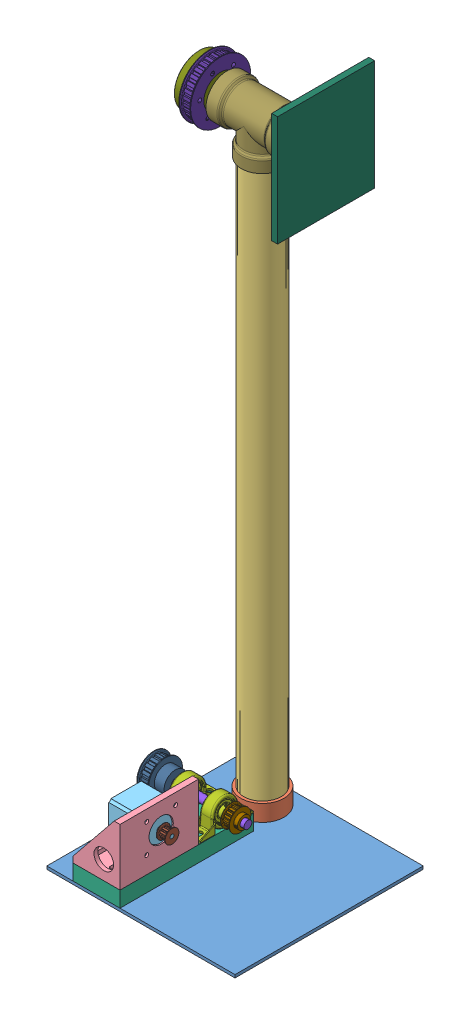
SolidWorks assembly Assem2, configuration Default. Lengths in mm.
Overall size (318.47 1076.8 338.99).
24 component instances, 19 part files, 3 mates.
Components (placement in the parent):
- Base Plate-1: Base Plate [Default] at (167.7214 104.1568 1085.8312) size (304.8 943.9 304.8)
  - Base Plate-1: Base Plate [Default] at origin size (304.8 4.76 304.8)
  - 1608T194_STANDARD-WALL BLACK ABS PIPE   PIPE FITTING-1: 1608T194_STANDARD-WALL BLACK ABS PIPE   PIPE FITTING [1608T194] at (88.9 4.7625 -260.35) x (0 -1 0) z (0 0 1) size (47.39 69.85 69.85)
  - 36_inch_abs_pipe-2: 36_inch_abs_pipe [Default] at (88.9 13.4572 -260.35) x (0.845689 0 -0.533676) z (0.533676 0 0.845689) size (60.32 914.4 60.32)
  - stepper bracket-1: stepper bracket [Default] at (118.5564 30.1625 0) x (0 0 -1) z (1 0 0) size (127 92.08 76.2)
  - stepper motor-1: stepper motor [Default] at (109.9204 52.8955 -94.742) x (0 1 0) z (1 0 0) size (56.13 56.13 74.42)
  - Spacer Block-1: Spacer Block [Default] at (118.5564 4.7625 0) x (-1 0 0) z (0 0 -1) size (76.2 25.4 215.9)
  - 5913K610_LOW-PROFILE MOUNTED BALL BEARING-1: 5913K610_LOW-PROFILE MOUNTED BALL BEARING [5913K61] at (54.6596 52.3875 -173.0375) x (0 0 1) z (-1 0 0) size (85.72 43.66 28.58)
  - 5913K610_LOW-PROFILE MOUNTED BALL BEARING-2: 5913K610_LOW-PROFILE MOUNTED BALL BEARING [5913K61] at (106.2533 52.3875 -173.0375) x (0 0 -1) z (1 0 0) size (85.72 43.66 28.58)
  - 1_2 inch shaft-1: 1_2 inch shaft [Default] at (152.6877 52.3875 -173.0375) x (0 0 1) z (-1 0 0) size (12.7 12.7 152.4)
  - 6495K749_TIMING BELT PULLEY-1: 6495K749_TIMING BELT PULLEY [6495K749] at (136.0126 52.3875 -173.0375) x (0 -0.188319 0.982108) z (1 0 0) size (34.92 34.92 20.62)
  - 6495K150_TIMING BELT PULLEY-1: 6495K150_TIMING BELT PULLEY [6495K15] at (17.7502 52.3875 -173.0375) x (0 -0.255878 -0.966709) z (1 0 0) size (54.76 54.76 34.92)
  - 6495K744_TIMING BELT PULLEY-1: 6495K744_TIMING BELT PULLEY [6495K744] at (125.77 80.9625 -66.675) x (0 0.924225 0.381849) z (-1 0 0) size (22.23 22.23 20.62)
- Rotator Head-1: Rotator Head [Default] at (186.6062 1127.1745 904.2529) x (1 0 0) z (0 0 -1) size (205.74 178.66 157.29)
  - 1608T155_STANDARD-WALL BLACK ABS PIPE   PIPE FITTING-1: 1608T155_STANDARD-WALL BLACK ABS PIPE   PIPE FITTING [1608T155] at (70.0151 51.5982 78.7717) size (114.3 91.5 68.71)
  - Bearing_Bushing_2-1: Bearing_Bushing_2 [Default] at (128.4351 51.5982 78.7717) x (0 -0.381849 0.924225) z (0 -0.924225 -0.381849) size (61.1 20.32 61.1)
  - Bearing_Bushing_2-2: Bearing_Bushing_2 [Default] at (11.5951 51.5982 78.7717) x (0 0.381849 -0.924225) z (0 -0.924225 -0.381849) size (61.1 20.32 61.1)
  - 6455K140_GENERAL PURPOSE PLASTIC BALL BEARING-1: 6455K140_GENERAL PURPOSE PLASTIC BALL BEARING [6455K14] at (121.7851 51.5982 78.7717) x (0 -0.160705 0.987003) z (-1 0 0) size (50.8 50.8 12.7)
  - 6455K140_GENERAL PURPOSE PLASTIC BALL BEARING-2: 6455K140_GENERAL PURPOSE PLASTIC BALL BEARING [6455K14] at (18.2451 51.5982 78.7717) x (0 -0.932635 -0.360822) z (1 0 0) size (50.8 50.8 12.7)
  - Delrin Shaft-2: Delrin Shaft [Default] at (-32.5549 51.5982 78.7717) x (0 0 -1) z (1 0 0) size (157.29 178.66 205.74)
  - 6086K321_QUICK-DISCONNECT BUSHING-1: 6086K321_QUICK-DISCONNECT BUSHING [6086K321] at (-32.5549 51.5982 78.7717) x (0 0.924225 0.381849) z (-1 0 0) size (80.96 80.96 34.92)
  - 6495K217_TIMING BELT PULLEY.step-1: 6495K217_TIMING BELT PULLEY.step [Default] at (-7.1549 51.5982 78.7717) x (0 -0.924225 -0.381849) z (1 0 0) size (97.28 97.28 19.05)
  - 95649A130_UHMW POLYETHYLENE FLAT WASHER-1: 95649A130_UHMW POLYETHYLENE FLAT WASHER [95649A130] at (128.1351 51.5982 78.7717) x (0 -1 0) z (0 0 1) size (44.45 3.3 44.45)
  - 91395A230_FIBERGLASS HEX NUT-1: 91395A230_FIBERGLASS HEX NUT [91395A230] at (141.74 51.5982 78.7717) x (0 0.99482 0.10165) z (0 -0.10165 0.99482) size (33.34 21.33 38.49)
Mates (geometry in assembly coordinates):
- Concentric1: concentric anti-aligned: cylinder of Base Plate-1/36_inch_abs_pipe-2 through (256.6214 1032.014 825.4812) axis (0 -1 0) radius 30.1625; cone of Rotator Head-1/1608T155_STANDARD-WALL BLACK ABS PIPE   PIPE FITTING-1 through (256.6214 1018.4262 825.4812) axis (0 1 0)
- Distance1: distance = 909.5069 mm anti-aligned: plane of Base Plate-1/Base Plate-1 through (167.7214 108.9193 1085.8312) normal (0 1 0); plane of Rotator Head-1/1608T155_STANDARD-WALL BLACK ABS PIPE   PIPE FITTING-1 through (290.9749 1018.4262 825.4812) normal (0 -1 0)
- Parallel1: parallel aligned: plane of Base Plate-1/Base Plate-1 through (167.7214 108.9193 1085.8312) normal (-1 0 0); plane of Rotator Head-1/Delrin Shaft-2 through (154.0514 1075.5762 825.4812) normal (-1 0 0)
